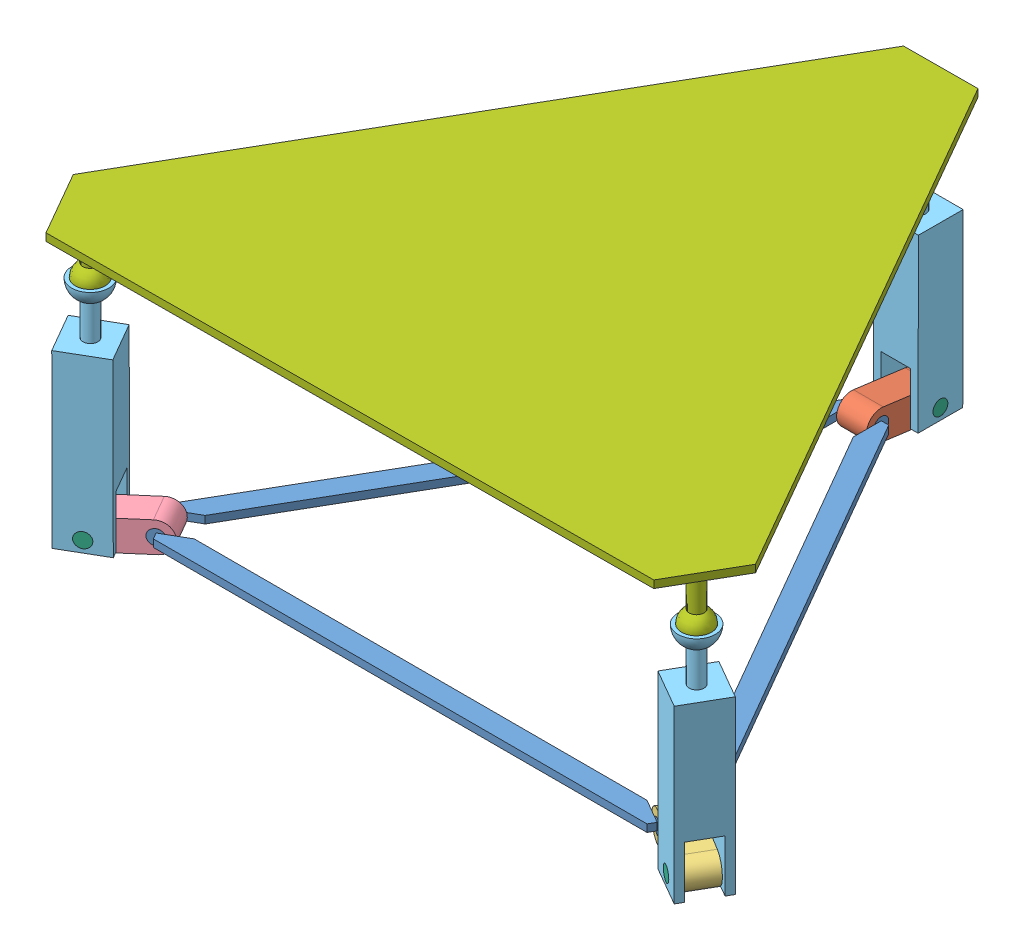
SolidWorks assembly platafomra_esfera, configuration Predeterminado. Lengths in mm.
Overall size (916.55 392.22 793.61).
11 component instances, 7 part files, 21 mates.
Components (placement in the parent):
- base-1: base [Predeterminado] at origin size (730.14 20 635.98)
- viela-1: viela [Predeterminado] at (0 0 -400) x (0 -0.1317 -0.99129) z (-1 0 0) size (110 40 40)
- viela2-1: viela2 [Predeterminado] at (346.4102 0 200) x (0.863875 -0.070425 0.498759) z (-0.5 0 0.866025) size (110 40 40)
- viela3-1: viela3 [Predeterminado] at (-346.4102 0 200) x (-0.858446 -0.132009 0.495624) z (0.5 0 0.866025) size (110 40 40)
- pilar-1: pilar [Predeterminado] at (0 -24.2189 -469.3582) x (1 0 0) z (0 0.00214 0.999998) size (60 300 60)
- pilar-2: pilar [Predeterminado] at (406.8741 -19.9298 234.9089) x (0.5 0 -0.866025) z (0.866025 -0.000564 0.5) size (60 300 60)
- pilar-3: pilar [Predeterminado] at (-406.4735 -24.2406 234.6776) x (0.5 0 0.866025) z (-0.866023 -0.002149 0.499999) size (60 300 60)
- pin inferior-1: pin inferior [Predeterminado] at (0 -9.219 -469.3903) x (1 0 0) z (0 -0.001262 0.999999) size (60 20 20)
- pin inferior-2: pin inferior [Predeterminado] at (406.8814 -4.9298 234.9131) x (0.5 0 -0.866025) z (0.866025 0.000029 0.5) size (60 20 20)
- pin inferior-3: pin inferior [Predeterminado] at (-406.5014 -9.2407 234.6937) x (0.5 0 0.866025) z (-0.866025 -0.00001 0.5) size (60 20 20)
- plataforma_soporte-2: plataforma_soporte [Predeterminado] at (-0.3745 347.2018 -0.2141) x (0.999986 0.005296 -0.000008) z (-0.000008 0.003027 0.999995) size (916.03 100 793.3)
Mates (geometry in assembly coordinates):
- Concéntrica1: concentric anti-aligned: cylinder of base-1 through (48.2843 0 -400) axis (-1 0 0) radius 10; cylinder of viela-1 through (-20 0 -400) axis (1 0 0) radius 10
- Coincidente1: coincident anti-aligned: plane of base-1 through (-20 5 0) normal (1 0 0); plane of viela-1 through (-20 0 -400) normal (-1 0 0)
- Concéntrica2: concentric aligned: cylinder of base-1 through (322.268 0 241.8154) axis (0.5 0 -0.866025) radius 10; cylinder of viela2-1 through (336.4102 0 217.3205) axis (0.5 0 -0.866025) radius 10
- Coincidente2: coincident anti-aligned: plane of base-1 through (-10 5 17.3205) normal (0.5 0 -0.866025); plane of viela2-1 through (336.4102 0 217.3205) normal (-0.5 0 0.866025)
- Concéntrica5: concentric aligned: cylinder of base-1 through (-322.268 0 241.8154) axis (-0.5 0 -0.866025) radius 10; cylinder of viela3-1 through (-336.4102 0 217.3205) axis (-0.5 0 -0.866025) radius 10
- Coincidente8: coincident anti-aligned: plane of base-1 through (-10 5 -17.3205) normal (0.5 0 0.866025); plane of viela3-1 through (-356.4102 0 182.6795) normal (-0.5 0 -0.866025)
- Concéntrica6: concentric aligned: cylinder of viela-1 through (-20 -4.9298 -469.8262) axis (1 0 0) radius 10; cylinder of pilar-1 through (-30 -4.9298 -469.8262) axis (1 0 0) radius 10
- Coincidente12: coincident anti-aligned: plane of viela-1 through (20 0 -400) normal (1 0 0); plane of pilar-1 through (20 50.0505 -499.8623) normal (-1 0 0)
- Concéntrica7: concentric aligned: cylinder of viela2-1 through (396.8814 -4.9298 252.2336) axis (0.5 0 -0.866025) radius 10; cylinder of pilar-2 through (391.8814 -4.9298 260.8939) axis (0.5 0 -0.866025) radius 10
- Coincidente13: coincident anti-aligned: plane of viela2-1 through (336.4102 0 217.3205) normal (-0.5 0 0.866025); plane of pilar-2 through (370.9275 50.0871 237.2491) normal (0.5 0 -0.866025)
- Concéntrica9: concentric anti-aligned: cylinder of viela3-1 through (-396.8814 -4.9298 252.2336) axis (-0.5 0 -0.866025) radius 10; cylinder of pilar-3 through (-421.8814 -4.9298 208.9323) axis (0.5 0 0.866025) radius 10
- Coincidente14: coincident anti-aligned: plane of viela3-1 through (-336.4102 0 217.3205) normal (0.5 0 0.866025); plane of pilar-3 through (-370.9319 50.0899 237.2516) normal (-0.5 0 -0.866025)
- Concéntrica10: concentric anti-aligned: cylinder of viela-1 through (-20 -4.9298 -469.8262) axis (1 0 0) radius 10; cylinder of pin inferior-1 through (30 -4.9298 -469.8262) axis (-1 0 0) radius 10
- Coincidente15: coincident aligned: plane of pilar-1 through (30 280.0899 -440.0131) normal (1 0 0); plane of pin inferior-1 through (30 -4.9298 -469.8262) normal (1 0 0)
- Concéntrica11: concentric anti-aligned: cylinder of viela2-1 through (396.8814 -4.9298 252.2336) axis (0.5 0 -0.866025) radius 10; cylinder of pin inferior-2 through (421.8814 -4.9298 208.9323) axis (-0.5 0 0.866025) radius 10
- Coincidente16: coincident aligned: plane of pilar-2 through (448.0013 280.0533 224.0127) normal (0.5 0 -0.866025); plane of pin inferior-2 through (421.8814 -4.9298 208.9323) normal (0.5 0 -0.866025)
- Concéntrica12: concentric aligned: cylinder of viela3-1 through (-396.8814 -4.9298 252.2336) axis (-0.5 0 -0.866025) radius 10; cylinder of pin inferior-3 through (-391.8814 -4.9298 260.8939) axis (-0.5 0 -0.866025) radius 10
- Coincidente17: coincident aligned: plane of pilar-3 through (-418.0241 280.0505 275.9873) normal (0.5 0 0.866025); plane of pin inferior-3 through (-391.8814 -4.9298 260.8939) normal (0.5 0 0.866025)
- Concéntrica13: concentric: sphere of pilar-3; sphere of plataforma_soporte-2
- Concéntrica14: concentric: sphere of pilar-2; sphere of plataforma_soporte-2
- Concéntrica15: concentric: sphere of pilar-1; sphere of plataforma_soporte-2
